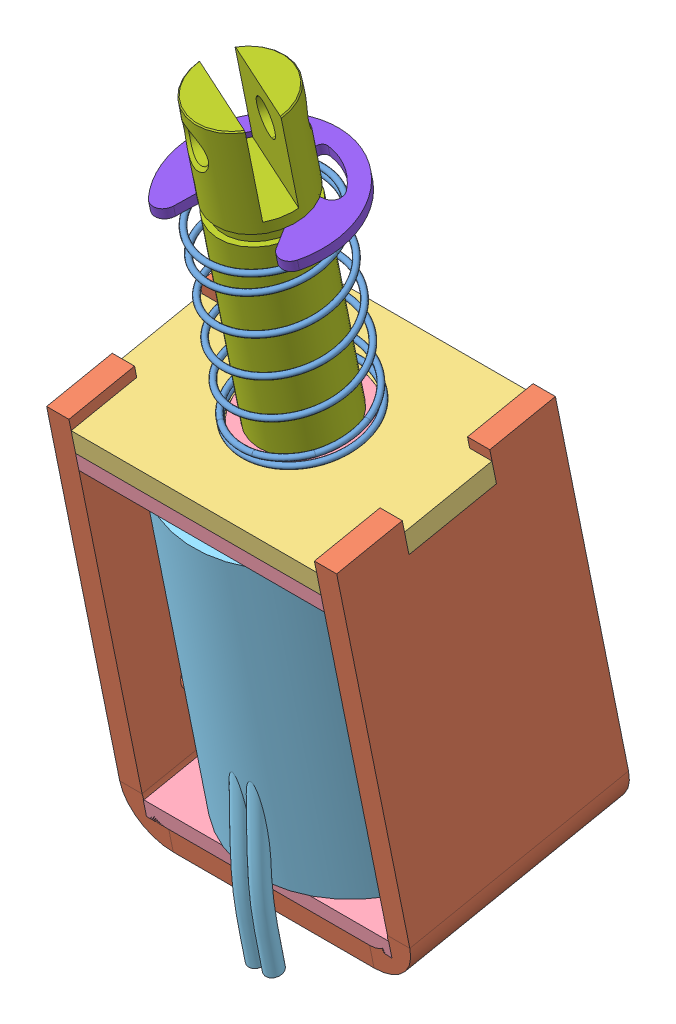
SolidWorks assembly 0837 solenoid, configuration Default. Lengths in mm.
Overall size (26 70.22 30.6).
10 component instances, 8 part files, 0 mates.
Components (placement in the parent):
- 0837 solenoid.stp-1: 0837 solenoid.stp [Default] at origin size (26 70.22 30.6)
  - Пружина сжатия.stp-1: Пружина сжатия.stp [Default] at (13 68.781 -203.166) x (-0.985424 -0.033783 0.166729) z (-0.170117 0.19569 -0.965798) size (11.59 18.02 11.65)
    - Пружина сжатия1.stp-1: Пружина сжатия1.stp [Default] at origin size (11.59 18.02 11.65)
  - base.stp-1: base.stp [Default] at (13 33.9516 -210.2231) x (1 0 0) z (0 0.198584 -0.980084) size (26 37 20)
  - cover.stp-1: cover.stp [Default] at (13 67.2745 -203.4712) x (0 -0.980084 -0.198584) z (-1 0 0) size (2 20 26)
  - frame.stp-1: frame.stp [Default] at (13 33.9516 -210.2231) x (0 0.980084 0.198584) z (0 0.198584 -0.980084) size (34 22 20)
  - coil.stp-1: coil.stp [Default] at (-6.5145 14.7377 -201.7104) x (-0.999808 -0.003892 0.019207) z (0.019597 -0.198546 0.979896) size (21.92 36.15 23.47)
  - nut.stp-1: nut.stp [Default] at (60.4092 27.3165 -162.6494) x (-0.703131 0.141205 -0.696899) z (-0.71106 -0.139631 0.689127) size (8 6 8)
  - kern.stp-1: kern.stp [Default] at (13 54.0999 -206.1407) x (0.386326 0.183167 -0.903992) z (0.922362 -0.076718 0.378632) size (8.04 42 8)
  - DIN 6799 - 7.stp-1: DIN 6799 - 7.stp [Default] at (12.4621 87.225 -203.4487) x (-0.990807 -0.026865 0.132588) z (0 -0.980084 -0.198584) size (14.3 11.59 0.9)
